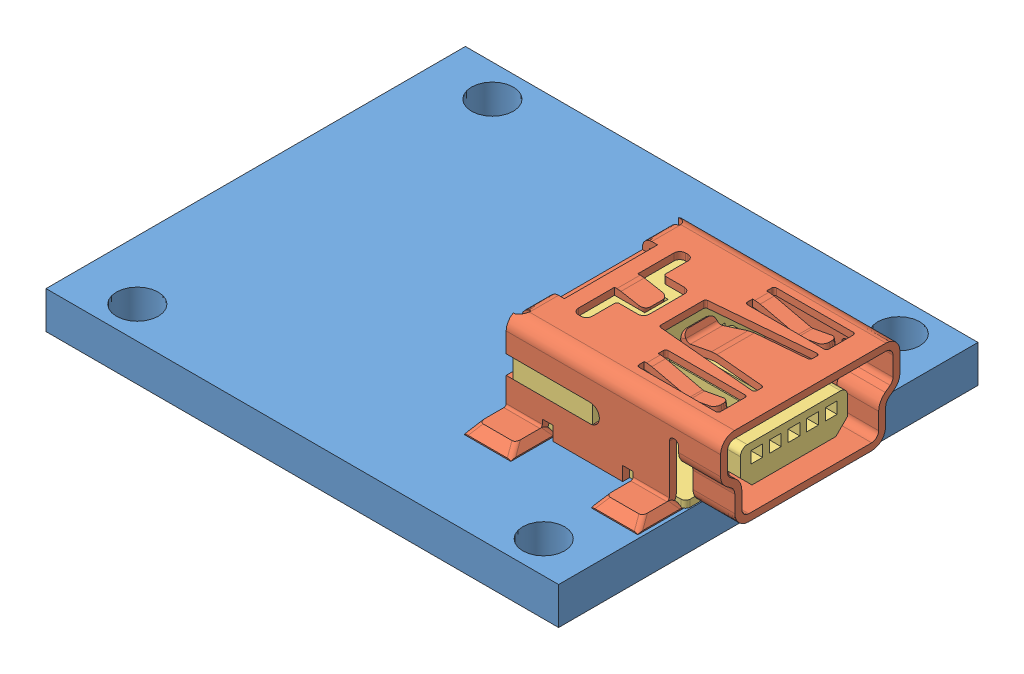
SolidWorks assembly Lithum battery charger, configuration Default. Lengths in mm.
Overall size (23.8 5.35 18).
5 component instances, 4 part files, 3 mates.
Components (placement in the parent):
- Li-Board-1: Li-Board [Default] at origin size (22 1.6 18)
- Li-MINIUSB - MEASURED-1: Li-MINIUSB - MEASURED [Default] at (28.38 1.65 -7.62) x (0 0 1) z (-1 0 0) size (10.9 4.8 9.4)
  - Li-MINIUSBSHELL-1: Li-MINIUSBSHELL [Default] at origin size (10.9 3.75 9.4)
  - Li-MINIUSBCORE-1: Li-MINIUSBCORE [Default] at (0 0 6.7) x (-1 0 0) z (0 0 -1) size (7.7 4.5 8.2)
  - MINI USB SOLDER-1: MINI USB SOLDER [Default] at (0 -0.05 -0.4) x (-1 0 0) z (0 0 -1) (suppressed, hidden)
Mates (geometry in assembly coordinates):
- Distance27: distance = 7.62 mm aligned: plane of MINIUSB - MEASURED-1 through (28.38 1.65 -7.62) normal (0 0 1); plane of assembly through (0 0 0) normal (0 0 1)
- Distance28: distance = 0.4 mm anti-aligned: plane of nano-board-1 through (28.78 1.6 -16.62) normal (1 0 0); plane of MINIUSB - MEASURED-1/MINIUSBSHELL-1 through (28.38 1.65 -7.62) normal (-1 0 0)
- Coincident56: coincident anti-aligned: plane of nano-board-1 through (0 1.6 0) normal (0 1 0); plane of MINIUSB - MEASURED-1/MINIUSBSHELL-1 through (28.38 1.6 -7.62) normal (0 -1 0)
